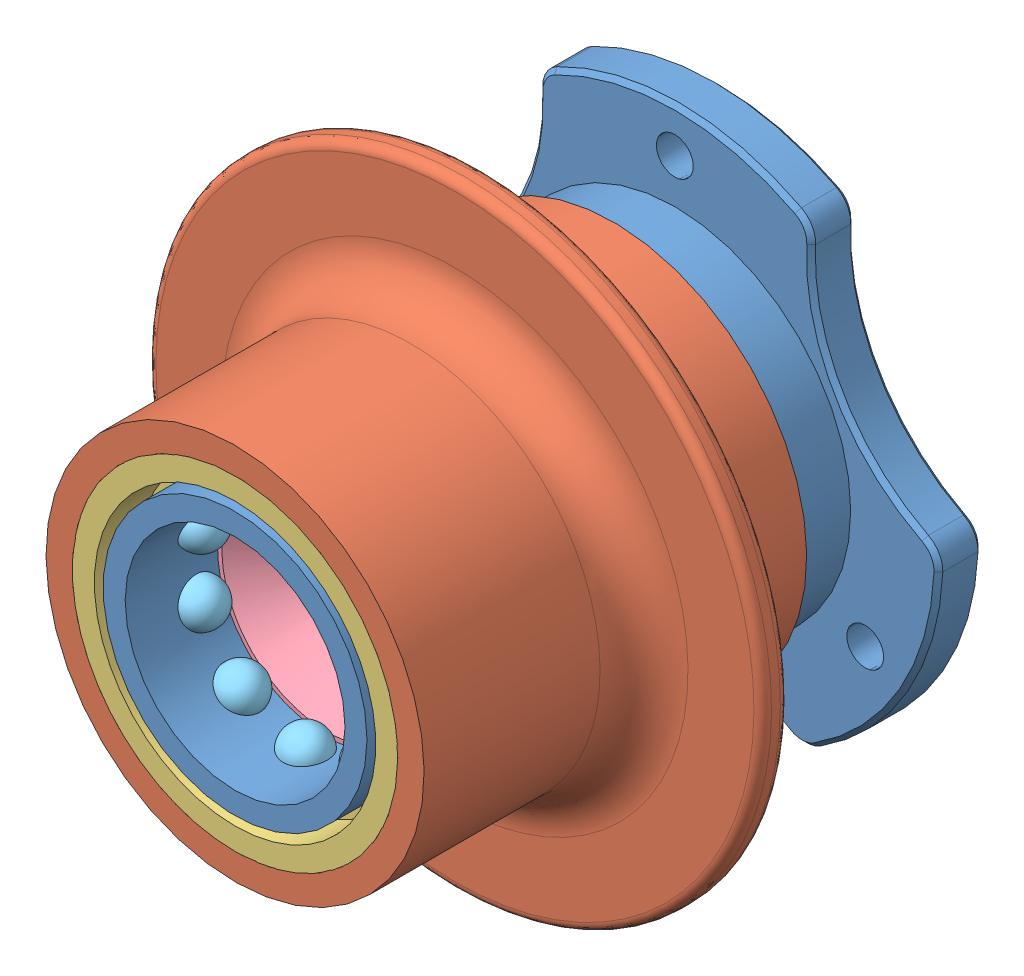
SolidWorks assembly Quick Release 1, configuration ﾃﾞﾌｫﾙﾄ. Lengths in mm.
Overall size (80.66 80.66 55).
16 component instances, 7 part files, 32 mates.
Components (placement in the parent):
- 1-1-1: 1-1 [ﾃﾞﾌｫﾙﾄ] at (-16.575 5.1943 90) size (59.95 55.8 55)
- 1-2-1: 1-2 [ﾃﾞﾌｫﾙﾄ] at (-16.575 5.1943 102) x (-0.986103 -0.166135 0) z (0 0 1) size (70 70 43)
- 1-3-1: 1-3 [ﾃﾞﾌｫﾙﾄ] at (-16.575 5.1943 145) x (-0.997775 -0.066677 0) z (0 0 -1) size (40 40 20)
- 1-5-1: 1-5 [ﾃﾞﾌｫﾙﾄ] at (-16.575 5.1943 134.5) x (-0.836075 -0.548615 0) z (0 0 -1) size (25 25 10)
- 1-4-1: 1-4 [ﾃﾞﾌｫﾙﾄ] at (-23.9223 -4.9184 137) size (5 5 5)
- 1-4-2: 1-4 [ﾃﾞﾌｫﾙﾄ] at (-16.575 -7.3057 137) x (0.757505 -0.002014 -0.652826) z (0.259947 -0.91637 0.304457) size (5 5 5)
- 1-4-4: 1-4 [ﾃﾞﾌｫﾙﾄ] at (-9.2277 -4.9184 137) x (0.59978 -0.145312 0.78686) z (-0.610771 0.552153 0.567525) size (5 5 5)
- 1-4-5: 1-4 [ﾃﾞﾌｫﾙﾄ] at (-4.6868 1.3316 137) x (0.883022 0.321394 -0.34202) z (0.418989 -0.211471 0.883022) size (5 5 5)
- 1-4-6: 1-4 [ﾃﾞﾌｫﾙﾄ] at (-28.4632 1.3316 137) x (0.720478 0.501888 -0.47856) z (0.592115 -0.085992 0.801253) size (5 5 5)
- 1-4-7: 1-4 [ﾃﾞﾌｫﾙﾄ] at (-4.6868 9.057 137) x (0.586824 0.492404 -0.642788) z (0.790379 -0.175893 0.586824) size (5 5 5)
- 1-4-12: 1-4 [ﾃﾞﾌｫﾙﾄ] at (-9.2277 15.307 137) x (0.37191 0.671322 -0.6411) z (0.907926 -0.119274 0.401802) size (5 5 5)
- 1-4-13: 1-4 [ﾃﾞﾌｫﾙﾄ] at (-16.575 17.6943 137) x (0.144729 0.779036 -0.610046) z (0.980991 -0.032428 0.191322) size (5 5 5)
- 1-4-16: 1-4 [ﾃﾞﾌｫﾙﾄ] at (-23.9223 15.307 137) x (-0.090859 0.870583 -0.48356) z (0.993983 0.109103 0.00966) size (5 5 5)
- 1-4-17: 1-4 [ﾃﾞﾌｫﾙﾄ] at (-28.4632 9.057 137) x (-0.407074 0.843286 -0.350941) z (0.912107 0.354897 -0.205205) size (5 5 5)
- Spring 1-1: Spring 1 [ﾃﾞﾌｫﾙﾄ] at (-16.575 5.1943 116) size (37.17 37.65 10)
- Spring 2-1: Spring 2 [ﾃﾞﾌｫﾙﾄ] at (-16.575 5.1943 104) size (22.6 22.92 21.5)
Mates (geometry in assembly coordinates):
- 同心円1: concentric: cylinder of 1-2-1 through (-16.575 5.1943 144) axis (0 0 -1) radius 20; cylinder of 1-1-1 through (-16.575 5.1943 103) axis (0 0 1) radius 12.5
- 同心円2: concentric: cylinder of 1-2-1 through (-16.575 5.1943 144) axis (0 0 -1) radius 20; cylinder of 1-3-1 through (-16.575 5.1943 140) axis (0 0 1) radius 16
- 一致2: coincident: plane of 1-2-1 through (-16.575 5.1943 144) normal (0 0 -1); plane of 1-3-1 through (-16.575 5.1943 144) normal (0 0 1)
- 同心円3: concentric: cylinder of 1-2-1 through (-16.575 5.1943 144) axis (0 0 -1) radius 20; cylinder of 1-5-1 through (-16.575 5.1943 124.5) axis (0 0 1) radius 12.5
- 正接1: tangent: cylinder of 1-3-1 through (-16.575 5.1943 145) axis (0 0 -1) radius 15; sphere of 1-4-1
- 正接4: tangent: cylinder of 1-3-1 through (-16.575 5.1943 145) axis (0 0 -1) radius 15; sphere of 1-4-2
- 正接6: tangent: cylinder of 1-3-1 through (-16.575 5.1943 145) axis (0 0 -1) radius 15; sphere of 1-4-4
- 正接7: tangent: cylinder of 1-3-1 through (-16.575 5.1943 145) axis (0 0 -1) radius 15; sphere of 1-4-5
- 正接8: tangent: cylinder of 1-3-1 through (-16.575 5.1943 145) axis (0 0 -1) radius 15; sphere of 1-4-6
- 正接9: tangent: cylinder of 1-3-1 through (-16.575 5.1943 145) axis (0 0 -1) radius 15; sphere of 1-4-7
- 正接14: tangent: cylinder of 1-3-1 through (-16.575 5.1943 145) axis (0 0 -1) radius 15; sphere of 1-4-12
- 正接15: tangent: cylinder of 1-3-1 through (-16.575 5.1943 145) axis (0 0 -1) radius 15; sphere of 1-4-13
- 正接18: tangent: cylinder of 1-3-1 through (-16.575 5.1943 145) axis (0 0 -1) radius 15; sphere of 1-4-16
- 正接19: tangent: cylinder of 1-3-1 through (-16.575 5.1943 145) axis (0 0 -1) radius 15; sphere of 1-4-17
- 一致3: coincident: plane of 1-1-1 through (-16.575 5.1943 145) normal (0 0 1); plane of 1-2-1 through (-16.575 5.1943 145) normal (0 0 1)
- 正接21: tangent: plane of 1-5-1 through (-16.575 5.1943 134.5) normal (0 0 1); sphere of 1-4-1
- 同心円21: concentric: cylinder of 1-1-1 through (-16.575 -20.6029 137) axis (0 1 0) radius 2.5; sphere of 1-4-2
- 同心円22: concentric: cylinder of 1-1-1 through (-41.1974 39.0841 137) axis (0.587785 -0.809017 0) radius 2.5; sphere of 1-4-4
- 正接24: tangent: cylinder of 1-1-1 through (8.0474 39.0841 137) axis (-0.587785 -0.809017 0) radius 2.5; sphere of 1-4-1
- 正接25: tangent: cylinder of 1-1-1 through (-51.2705 -6.079 137) axis (0.951057 0.309017 0) radius 2.5; sphere of 1-4-6
- 正接26: tangent: cylinder of 1-1-1 through (18.1205 -6.079 137) axis (-0.951057 0.309017 0) radius 2.5; sphere of 1-4-17
- 正接27: tangent: cylinder of 1-1-1 through (-41.1974 39.0841 137) axis (0.587785 -0.809017 0) radius 2.5; sphere of 1-4-16
- 正接28: tangent: cylinder of 1-1-1 through (-16.575 -20.6029 137) axis (0 1 0) radius 2.5; sphere of 1-4-13
- 正接29: tangent: cylinder of 1-1-1 through (8.0474 39.0841 137) axis (-0.587785 -0.809017 0) radius 2.5; sphere of 1-4-12
- 同心円23: concentric: cylinder of 1-1-1 through (-51.2705 -6.079 137) axis (0.951057 0.309017 0) radius 2.5; sphere of 1-4-7
- 正接31: tangent: cylinder of 1-1-1 through (18.1205 -6.079 137) axis (-0.951057 0.309017 0) radius 2.5; sphere of 1-4-5
- 距離1: distance = 1 mm: plane of Spring 1-1 through (-16.575 5.1943 116) normal (0 0 1); plane of 1-1-1 through (-16.575 5.1943 115) normal (0 0 1)
- 一致6: coincident: plane of Spring 1-1 through (-16.575 5.1943 116) normal (0 1 0); plane of 1-1-1 through (-16.575 5.1943 90) normal (0 1 0)
- 一致7: coincident: plane of Spring 1-1 through (-16.575 5.1943 116) normal (1 0 0); plane of 1-1-1 through (-16.575 5.1943 90) normal (1 0 0)
- 正接38: tangent: plane of 1-5-1 through (-16.575 5.1943 124.5) normal (0 0 -1); torus of Spring 2-1
- 一致8: coincident: plane of 1-1-1 through (-16.575 5.1943 90) normal (0 1 0); plane of Spring 2-1 through (-16.575 5.1943 104) normal (0 1 0)
- 一致9: coincident: plane of 1-1-1 through (-16.575 5.1943 90) normal (1 0 0); plane of Spring 2-1 through (-16.575 5.1943 104) normal (1 0 0)
